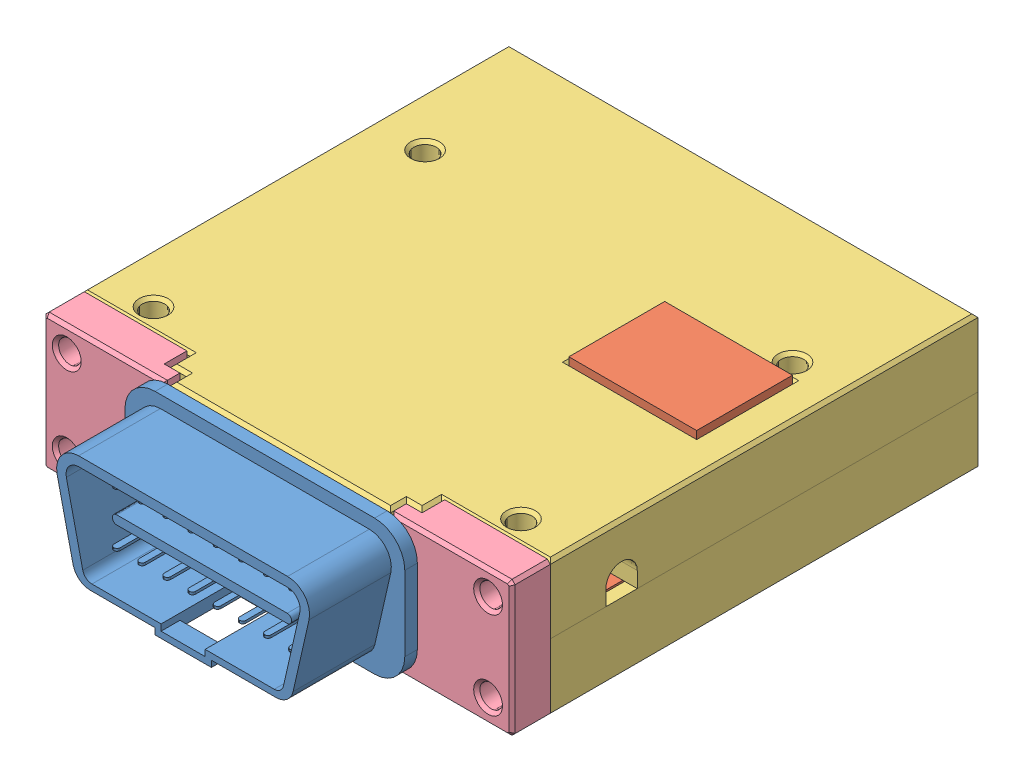
SolidWorks assembly Assem1, configuration Default. Lengths in mm.
Overall size (74.6 22.25 89.1).
4 component instances, 4 part files, 3 mates.
Components (placement in the parent):
- obd2 connector model 1-1: obd2 connector model 1 [Default] at (-1.9959 -0.31 -2.9362) size (44.5 21.5 21.6)
- perfboard-1: perfboard [Default] at (-1.9959 -1.91 -34.0362) size (70 13.1 50)
- box^Assem1-1: box^Assem1 [Default] at origin size (74.6 21.7 73.6) (virtual)
- lid^Assem1-1: lid^Assem1 [Default] at origin size (74.6 21.5 6.1) (virtual)
Mates (geometry in assembly coordinates):
- Distance1: distance = 1 mm anti-aligned: plane of perfboard-1 through (-36.9959 -0.31 -9.0362) normal (0 0 1); plane of obd2 connector model 1-1 through (-1.9959 -0.31 -8.0362) normal (0 0 -1)
- Coincident3: coincident anti-aligned: plane of obd2 connector model 1-1 through (-1.9959 -0.31 -2.9362) normal (1 0 0); plane of perfboard-1 through (-1.9959 -1.91 -34.0362) normal (-1 0 0)
- Coincident4: coincident aligned: plane of obd2 connector model 1-1 through (-1.9959 -0.31 -2.9362) normal (0 1 0); plane of perfboard-1 through (-1.9959 -0.31 -34.0362) normal (0 1 0)
